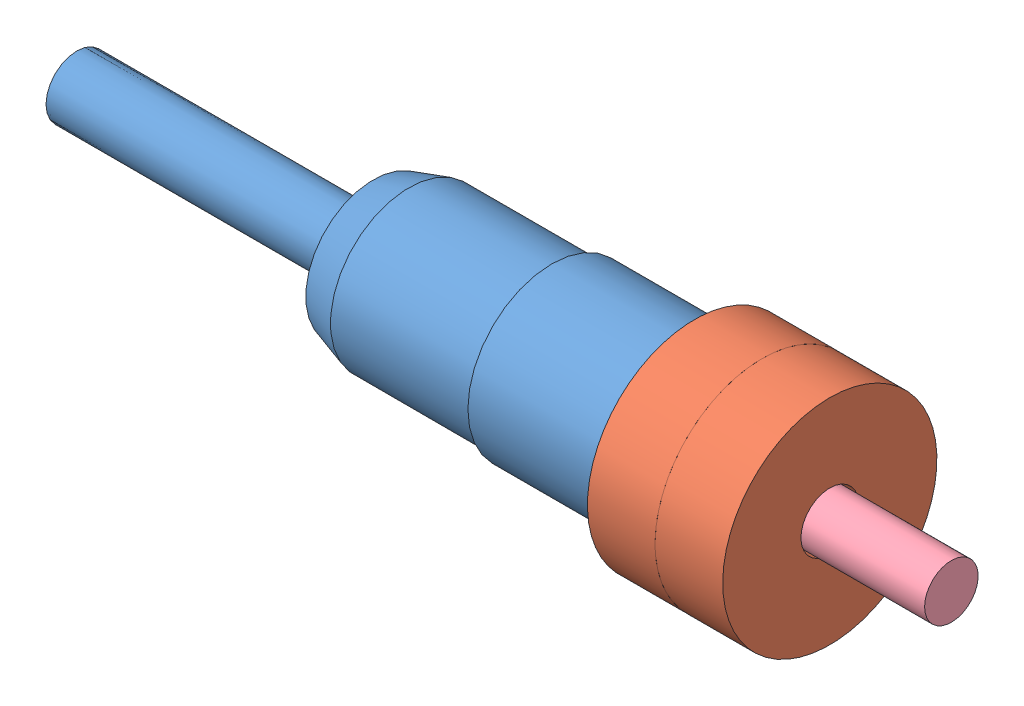
SolidWorks assembly bed calibration device, configuration Default. Lengths in mm.
Overall size (49 12.48 12.48).
6 component instances, 4 part files, 8 mates.
Components (placement in the parent):
- metal knurl-1: metal knurl [Default] at (-2.1532 2.6055 -5.8442) size (34.61 9.4 9.4)
- Magnet (12x3.79mm)-1: Magnet (12x3.79mm) [Default] at (313.6925 56.1204 -10.3541) x (0 0.023613 0.999721) z (-1 0 0) size (12 12 3.79)
- countersunk flat head cross recess screw_iso1-1: countersunk flat head cross recess screw_iso1 [ISO 7046-1 - M3 x 6 - Z --- 6N] at (313.1507 79.3124 -5.8442) x (-1 0 0) z (0 0.092314 -0.99573) size (6 5.5 5.5)
- countersunk flat head cross recess screw_iso1-2: countersunk flat head cross recess screw_iso1 [ISO 7046-1 - M3 x 10 - Z --- 10N] at (314.2925 79.3124 -5.8442) x (1 0 0) z (0 0.392827 0.919612) size (10 5.5 5.5)
- Magnet (12x3.79mm)-2: Magnet (12x3.79mm) [Default] at (313.6925 102.5788 -9.9525) x (0 -0.040894 0.999163) z (1 0 0) size (12 12 3.79)
- sleve-1: sleve [Default] at (310.0825 118.8102 344.5108) x (0 0.943746 -0.330671) z (1 0 0) (suppressed, hidden)
Mates (geometry in assembly coordinates):
- Coincident787258: coincident anti-aligned: plane of Magnet (12x3.79mm)-1 through (309.9025 79.3124 -5.8442) normal (-1 0 0); plane of metal knurl-1 through (309.9025 2.6055 -5.8442) normal (1 0 0)
- Coincident786953: coincident: cone of Magnet (12x3.79mm)-1 through (313.6925 79.3124 -5.8442) axis (-1 0 0); cone of countersunk flat head cross recess screw_iso-1 through (312.7507 79.3124 -5.8442) axis (-1 0 0)
- Concentric401189: concentric aligned: cylinder of Magnet (12x3.79mm)-2 through (317.4825 79.3124 -5.8442) axis (-1 0 0) radius 6; cylinder of sleve-1 through (317.4825 79.3124 -5.8442) axis (-1 0 0) radius 5.992
- Coincident78718798: coincident: plane of assembly; plane of sleve-1 through (317.4825 79.3124 -5.8442) normal (-1 0 0); plane of Magnet (12x3.79mm)-2 through (317.4825 79.3124 -5.8442) normal (1 0 0)
- Concentric4005713: concentric anti-aligned: cylinder of Magnet (12x3.79mm)-1 through (309.9025 79.3124 -5.8442) axis (1 0 0) radius 6; cylinder of sleve-1 through (317.4825 79.3124 -5.8442) axis (-1 0 0) radius 8.492
- Coincident78718800: coincident aligned: cone of Magnet (12x3.79mm)-2 through (313.6925 79.3124 -5.8442) axis (1 0 0); cone of countersunk flat head cross recess screw_iso-2 through (314.6925 79.3124 -5.8442) axis (1 0 0)
- Concentric4005715: concentric aligned: cylinder of metal knurl-1 through (275.2938 79.3124 -5.8442) axis (-1 0 0) radius 4.7; cylinder of sleve-1 through (317.4825 79.3124 -5.8442) axis (-1 0 0) radius 5.992
- Coincident78718801: coincident anti-aligned: plane of Magnet (12x3.79mm)-1 through (313.6925 79.3124 -5.8442) normal (1 0 0); plane of Magnet (12x3.79mm)-2 through (313.6925 79.3124 -5.8442) normal (-1 0 0)
